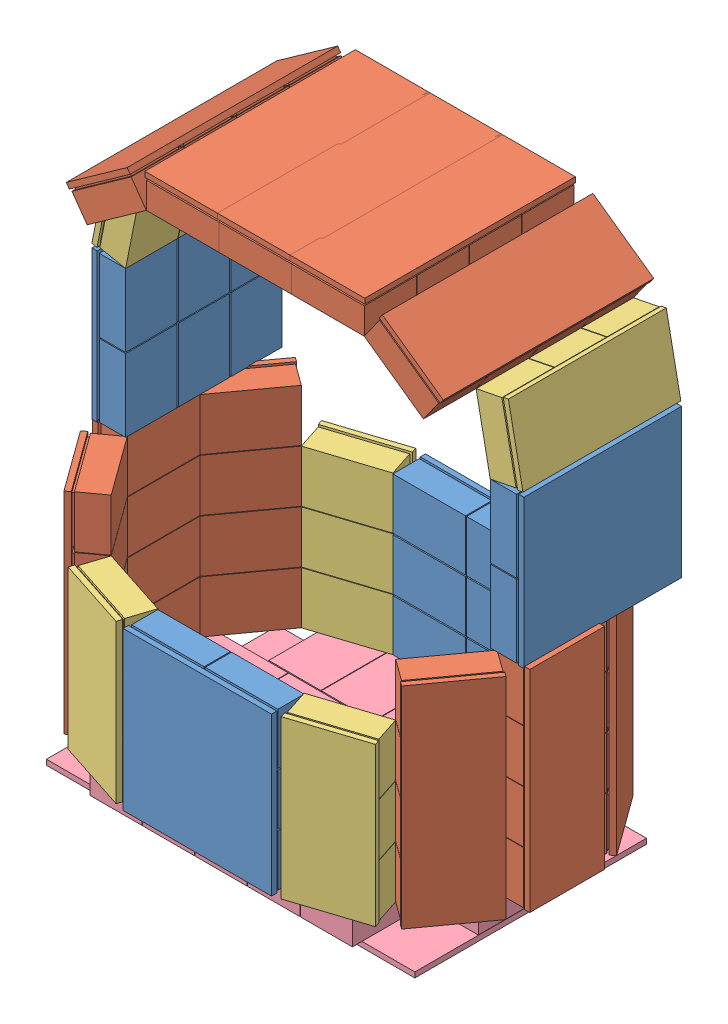
SolidWorks assembly LineofResponce, configuration Default. Lengths in mm.
Overall size (495.24 509.15 340.33).
28 component instances, 5 part files, 4 mates.
Components (placement in the parent):
- woman body-1: woman body [Default] at (325.4407 484.4544 221.086) size (637.83 301.02 817.55) (hidden)
- Detector1n3_3-1: Detector1n3_3 [Default] at (49.8582 665.158 553.2219) x (1 0 0) z (0 -1 0) size (495.24 340.33 231)
  - Detector1n2_changed-1: Detector1n2_changed [Default] at (214.6875 32.8122 259.0633) size (495.24 340.33 200.99)
    - top_bottomDetector2-1: top_bottomDetector2 [Default] at (5.3043 60.2155 74.3483) size (141 32 149.74)
    - CshapedDetector2-1: CshapedDetector2 [Default] at (104.3454 -76.5763 -85.899) x (0.951057 0.309017 0) z (0 0 1) size (177.89 270.84 200)
      - 1Detector-2: 1Detector [Default] at (173.0714 153.2337 184.2598) x (0.809017 0.587785 0) z (0 0 1) size (71 32 200)
      - 1Detector-4: 1Detector [Default] at (223.2683 222.3237 184.2598) x (0.309017 0.951057 0) z (0 0 1) size (71 32 200)
      - 1Detector-5: 1Detector [Default] at (223.2683 307.7237 184.2598) x (-0.309017 0.951057 0) z (0 0 1) size (71 32 200)
      - 1Detector_3modules-1: 1Detector_3modules [Default] at (91.8512 126.8436 209.2598) size (71 32 150)
      - 1Detector_3modules-2: 1Detector_3modules [Default] at (173.0714 376.8138 209.2598) x (-0.809017 0.587785 0) z (0 0 1) size (71 32 150)
    - CshapedDetector2-2: CshapedDetector2 [Default] at (-23.7368 484.2959 -85.899) x (-0.951057 -0.309017 0) z (0 0 1) size (177.89 270.84 200)
      - 1Detector-2: 1Detector [Default] at (173.0714 153.2337 184.2598) x (0.809017 0.587785 0) z (0 0 1) size (71 32 200)
      - 1Detector-4: 1Detector [Default] at (223.2683 222.3237 184.2598) x (0.309017 0.951057 0) z (0 0 1) size (71 32 200)
      - 1Detector-5: 1Detector [Default] at (223.2683 307.7237 184.2598) x (-0.309017 0.951057 0) z (0 0 1) size (71 32 200)
      - 1Detector_3modules-1: 1Detector_3modules [Default] at (91.8512 126.8436 209.2598) size (71 32 150)
      - 1Detector_3modules-2: 1Detector_3modules [Default] at (173.0714 376.8138 209.2598) x (-0.809017 0.587785 0) z (0 0 1) size (71 32 150)
    - top_bottomDetector2-2: top_bottomDetector2 [Default] at (75.3043 347.5042 74.3483) x (-1 0 0) z (0 0 1) size (141 32 149.74)
  - Detector3-1: Detector3 [Default] at (255.9219 239.5761 488.4241) x (0 -1 0) z (1 0 0) size (239.5 31 350)
- Detector_posterial2-1: Detector_posterial2 [Default] at (218.3959 771.2045 927.1336) x (1 0 0) z (0 0 -1) size (410.4 279.65 200.24)
  - 1Detector-1: 1Detector [Default] at (83.9721 85.3161 150.6758) size (71 32 200)
  - 1Detector-2: 1Detector [Default] at (152.9721 85.3161 150.6758) size (71 32 200)
  - 1Detector-3: 1Detector [Default] at (14.9721 85.3161 150.6758) size (71 32 200)
  - 1Detector-4: 1Detector [Default] at (-66.1879 111.2254 150.6758) x (0.815027 -0.579423 0) z (0 0 1) size (71 32 200)
  - 1Detector-5: 1Detector [Default] at (234.132 111.2254 150.6758) x (0.815027 0.579423 0) z (0 0 1) size (71 32 200)
  - 1Detector_3modules-1: 1Detector_3modules [Default] at (-113.8805 184.8905 175.6758) x (0.19509 -0.980785 0) z (0 0 1) size (71 32 150)
  - 1Detector_3modules-2: 1Detector_3modules [Default] at (281.8247 184.8905 175.6758) x (0.19509 0.980785 0) z (0 0 1) size (71 32 150)
  - top_bottomDetector2-1: top_bottomDetector2 [Default] at (289.1701 259.4705 125.9183) x (0 1 0) z (0 0 1) size (141 32 149.74)
  - top_bottomDetector2-2: top_bottomDetector2 [Default] at (-121.226 329.4705 125.9183) x (0 -1 0) z (0 0 1) size (141 32 149.74)
Mates (geometry in assembly coordinates):
- Coincident2: coincident anti-aligned: line of ? through (525.8671 534.1982 703.9257) axis (0 0 1); line of ? through (525.8671 534.1982 753.4257) axis (0 0 -1)
- Coincident3: coincident: point of ?; point of ?
- Parallel1: parallel aligned: plane of Detector1n3_3-1/Detector1n2_changed-1/CshapedDetector2-1/1Detector-4 through (512.5301 307.734 789.8939) normal (1 0 0); plane of Detector_posterial2-1/top_bottomDetector2-1 through (507.5661 511.734 801.2154) normal (1 0 0)
- Coincident5: coincident anti-aligned: line of Detector1n3_3-1/Detector1n2_changed-1/CshapedDetector2-2/1Detector-4 through (129.1699 407.234 755.3939) axis (0 0 1); line of Detector_posterial2-1/top_bottomDetector2-2 through (129.1699 407.234 825.9578) axis (0 0 -1)
